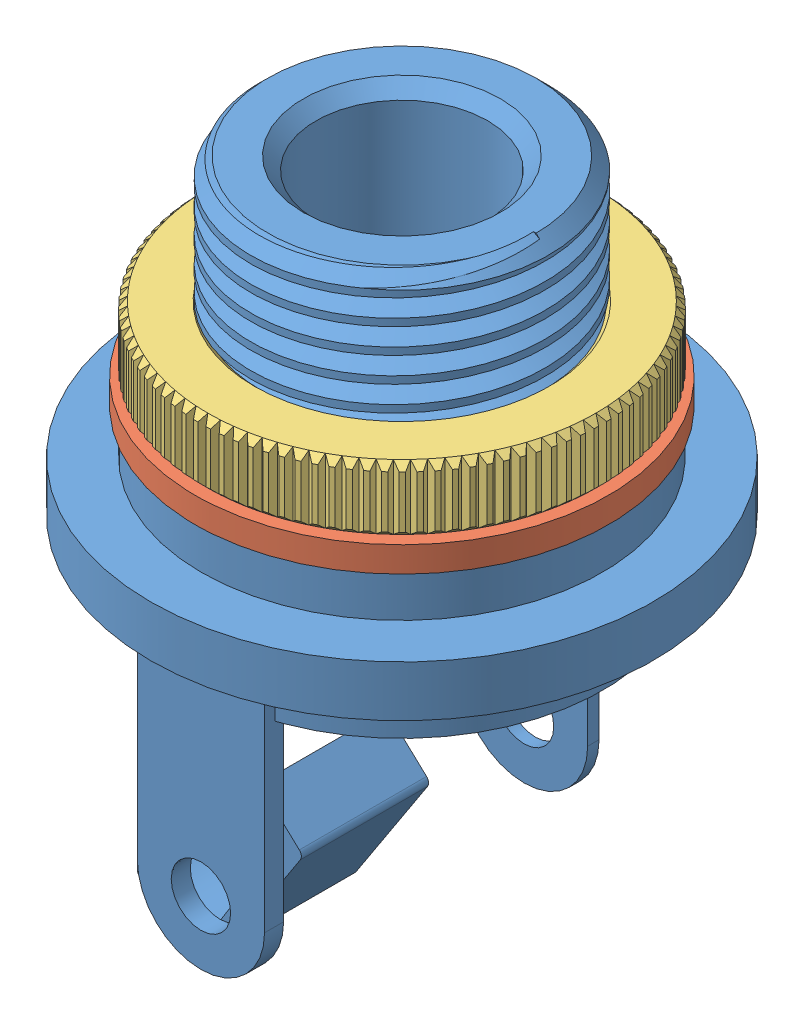
SolidWorks assembly 8th in female audio jack, configuration Default. Lengths in mm.
Overall size (10.03 14.35 10.03).
3 component instances, 3 part files, 4 mates.
Components (placement in the parent):
- 8th in female audio jack-1: 8th in female audio jack [Default] at (17.7328 19.0048 -20.9915) size (10.03 14.35 10.03)
- 8th in washer-1: 8th in washer [Default] at (17.7328 19.8938 -20.9915) x (0.999803 0 -0.019825) z (0.019825 0 0.999803) size (8.26 0.51 8.26)
- 8th in nut-1: 8th in nut [Default] at (17.7328 20.4018 -20.9915) size (8 1.3 8)
Mates (geometry in assembly coordinates):
- Concentric1: concentric anti-aligned: circle of 8th in female audio jack-1; circle of 8th in washer-1
- Coincident1: coincident anti-aligned: plane of 8th in female audio jack-1 through (17.7328 19.8938 -20.9915) normal (0 1 0); plane of 8th in washer-1 through (17.7328 19.8938 -20.9915) normal (0 -1 0)
- Concentric2: concentric aligned: cylinder of 8th in female audio jack-1 through (17.7328 24.2118 -20.9915) axis (0 -1 0) radius 2.9337; circle of 8th in nut-1
- Coincident2: coincident anti-aligned: plane of 8th in washer-1 through (17.7328 20.4018 -20.9915) normal (0 1 0); plane of 8th in nut-1 through (17.7328 20.4018 -20.9915) normal (0 -1 0)
